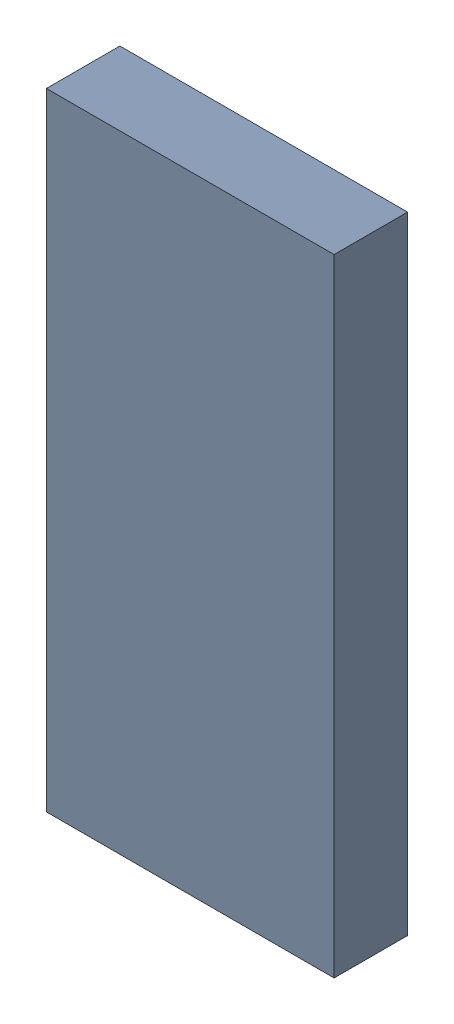
SolidWorks assembly TDA5340_TDA1, configuration Standard. Lengths in mm.
Overall size (4.5 9.8 1.15).
2 component instances, 1 part files, 0 mates.
Components (placement in the parent):
- 885542512-1: 885542512 [Standard] at (-0.42 50.24 0.05) size (4.5 9.8 1.15)
  - Extruded_13-1: Extruded_13 [Standard] at origin size (4.5 9.8 1.15)
